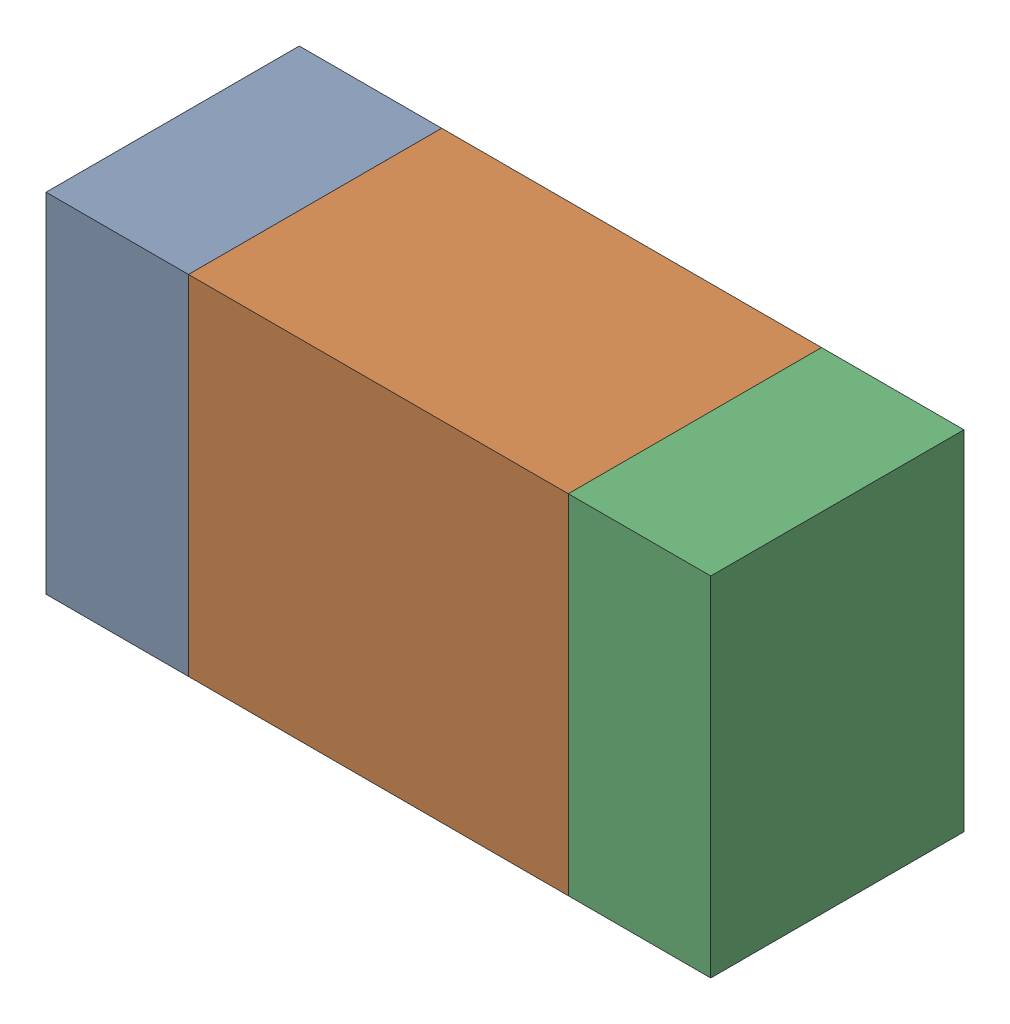
SolidWorks assembly R319_2PCB, configuration Default. Lengths in mm.
Overall size (1.05 0.55 0.4).
6 component instances, 2 part files, 0 mates.
Components (placement in the parent):
- 854785432-1: 854785432 [Default] at (135.1876 96.0999 -2.0638) size (0.22 0.55 0.4)
  - Extruded-1: Extruded [Default] at origin size (0.22 0.55 0.4)
- 854785568-1: 854785568 [Default] at (135.6001 96.0999 -2.0638) size (0.6 0.55 0.4)
  - Extruded_2-1: Extruded_2 [Default] at origin size (0.6 0.55 0.4)
- 854785432-2: 854785432 [Default] at (136.0126 96.0999 -2.0638) size (0.22 0.55 0.4)
  - Extruded-1: Extruded [Default] at origin size (0.22 0.55 0.4)
